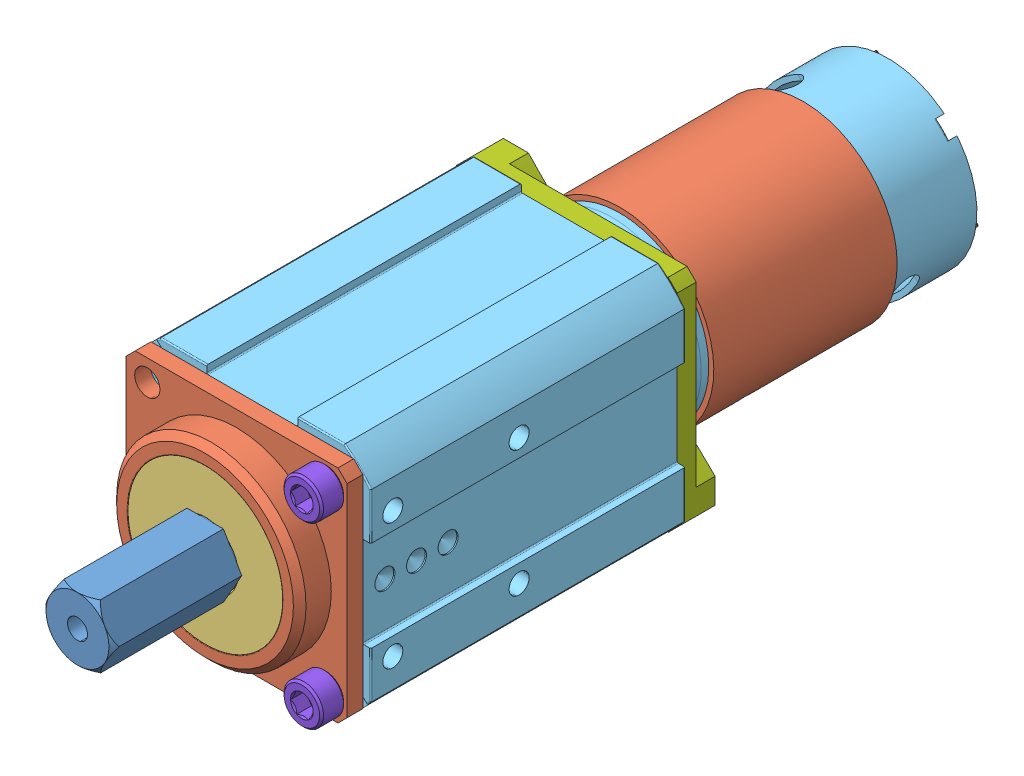
SolidWorks assembly 2018-321-A, configuration Default. Lengths in mm.
Overall size (53.25 53.25 170.06).
44 component instances, 23 part files, 4 mates.
Components (placement in the parent):
- am-3758+-+100_1+-+57+Sport Banebots-1: am-3758+-+100_1+-+57+Sport Banebots [Default] at origin size (48.57 48.57 106.05)
  - am-XXXX - 57 Sport 500 Hex Output Plug-1: am-XXXX - 57 Sport 500 Hex Output Plug [Default] at (24.8149 30.9071 37.1991) size (44.45 44.45 56.9)
    - am-XXXX - 57 Sport 500 Hex Shaft-1: am-XXXX - 57 Sport 500 Hex Shaft [Default] at (0 0 6.2738) x (0.999982 0.006056 0) z (0 0 1) size (16.1 12.67 56.9)
    - Output Block-1: Output Block [Default] at origin size (44.45 44.45 20.32)
    - FR8ZZ Bearing-1: FR8ZZ Bearing [Default] at (8.9053 -5.9773 -13.8938) x (0.999973 0.007281 0) z (0 0 1) size (31.75 31.75 7.95)
    - FR8ZZ Bearing-2: FR8ZZ Bearing [Default] at (5.8713 8.9755 6.2738) x (0.923728 0.383049 0) z (0 0 -1) size (31.75 31.75 7.95)
    - retaining Ring 0500 - Mcm 98410A122_98410A122-1: retaining Ring 0500 - Mcm 98410A122_98410A122 [Default] at (0 0 -14.3891) x (0 0 1) z (-0.999848 0.017452 0) size (0.89 16.1 14.34)
  - am-XXXX - 57 Sport 3 Stage Ring Gear Housing-1: am-XXXX - 57 Sport 3 Stage Ring Gear Housing [Default] at (24.8149 30.9071 2.4011) size (47.68 47.68 63.27)
  - Thrust washer - 775 Sport-1: Thrust washer - 775 Sport [Default] at (24.8149 30.9071 -27.7241) x (0.992053 0.125818 0) z (0 0 1) size (31 31 1.52)
  - am-3765 - 57 Sport Motor Block-1: am-3765 - 57 Sport Motor Block [Default] at (24.8149 30.9071 -33.0319) x (0 1 0) z (0 0 1) size (45.76 47.07 8.89)
  - 10-32 X 375 SHCS_90128A940-1: 10-32 X 375 SHCS_90128A940 [Default] at (42.7754 48.8676 27.6741) x (-0.100111 -0.994976 0) z (0 0 -1) size (7.92 7.92 14.58)
  - 10-32 X 375 SHCS_90128A940-2: 10-32 X 375 SHCS_90128A940 [Default] at (6.8543 12.9466 27.6741) x (0.058911 -0.998263 0) z (0 0 -1) size (7.92 7.92 14.58)
  - 5_1 HD Output Stage-1: 5_1 HD Output Stage [Default] at (-68.9808 196.0711 114.0764) x (-0.524 0.851718 0) z (0 0 -1) size (39.35 39.35 20.95)
    - 5_1 HD Output Stage Carrier Plate-1: 5_1 HD Output Stage Carrier Plate [Default] at (-189.8221 -6.6586 94.2255) size (30.99 30.99 20.93)
    - 18T Long Planet Gear-1: 18T Long Planet Gear [Default] at (-200.8282 -6.6808 106.2401) x (0 0 1) z (0.923728 0.383049 0) size (13.43 13.84 14)
    - 18T Long Planet Gear-2: 18T Long Planet Gear [Default] at (-189.8444 4.3475 106.2401) x (0 0 1) z (0.383049 -0.923728 0) size (13.43 13.84 14)
    - 18T Long Planet Gear-3: 18T Long Planet Gear [Default] at (-178.816 -6.6363 106.2401) x (0 0 1) z (-0.923728 -0.383049 0) size (13.43 13.84 14)
    - 18T Long Planet Gear-4: 18T Long Planet Gear [Default] at (-189.7998 -17.6647 106.2401) x (0 0 1) z (-0.383049 0.923728 0) size (13.43 13.84 14)
  - am-XXXX - 5_1 Sun Gear 4_1 Carrier Plate-1: am-XXXX - 5_1 Sun Gear 4_1 Carrier Plate [Default] at (24.8149 30.9071 -13.6055) x (-0.898594 -0.43878 0) z (0 0 -1) size (40.05 39.58 20.09)
    - 5_1 Sun Gear 57 Sport Stage Carrier Plate-1: 5_1 Sun Gear 57 Sport Stage Carrier Plate [Default] at origin size (31.12 31.12 12.6)
    - 12T Sun Gear-1: 12T Sun Gear [Default] at (3.5865 0.6306 4.6787) x (0 0 1) z (-0.923728 -0.383049 0) size (12.75 9.53 9.53)
    - 16T Planet Gear-1: 16T Planet Gear [Default] at (0.9198 10.3381 9.8136) x (0 0 -1) z (-0.923728 -0.383049 0) size (7.09 12.42 12.42)
    - 16T Planet Gear-2: 16T Planet Gear [Default] at (12.4377 -0.8696 9.8136) x (0 0 -1) z (-0.85131 -0.524663 0) size (7.09 12.42 12.42)
    - 16T Planet Gear-3: 16T Planet Gear [Default] at (1.1732 -12.0926 9.8136) x (0 0 -1) z (-0.777574 -0.628792 0) size (7.09 12.42 12.42)
    - 16T Planet Gear-4: 16T Planet Gear [Default] at (-10.1307 -0.6136 9.8136) x (0 0 -1) z (-0.715577 -0.698533 0) size (7.09 12.42 12.42)
  - am-XXXX - 5_1 Stage-1: am-XXXX - 5_1 Stage [Default] at (24.8149 30.9071 -1.0975) x (-0.884358 0.46681 0) z (0 0 -1) size (37.89 36.82 20.09)
    - 5_1 Stage Carrier Plate-1: 5_1 Stage Carrier Plate [Default] at origin size (31.12 31.12 12.6)
    - 18T Short Planet Gear-1: 18T Short Planet Gear [Default] at (-0.9034 11.1608 11.3032) x (0 0 -1) z (0.019286 0.999814 0) size (7 13.84 14)
    - 18T Short Planet Gear-2: 18T Short Planet Gear [Default] at (9.5654 0.4561 11.3032) x (0 0 -1) z (-0.139481 0.990225 0) size (7 13.84 14)
    - 18T Short Planet Gear-3: 18T Short Planet Gear [Default] at (-1.0383 -10.2271 11.3032) x (0 0 -1) z (-0.264433 0.964404 0) size (7 13.84 14)
    - 18T Short Planet Gear-4: 18T Short Planet Gear [Default] at (-11.6179 0.2284 11.3032) x (0 0 -1) z (-0.353176 0.935557 0) size (7 13.84 14)
    - 12T Sun Gear-1: 12T Sun Gear [Default] at (-3.5865 -0.6306 4.6787) x (0 0 1) z (0.923728 0.383049 0) size (12.75 9.53 9.53)
  - 10-32 X 375 SHCS_90128A940-3: 10-32 X 375 SHCS_90128A940 [Default] at (42.7754 12.9466 27.6741) x (0.058911 -0.998263 0) z (0 0 -1) size (7.92 7.92 14.58)
- CCL-9015-am-0912-1: CCL-9015-am-0912 [Default] at (22.8966 30.5762 -61.5239) x (0 0 -1) z (-0.707107 -0.707107 0) size (82.02 37.83 37.47)
  - AM-0912 terminal-1: AM-0912 terminal [Default] at (29.27 -13.055 -1.5854) size (10.06 0.6 3.8)
  - AM-0912 output bushing-1: AM-0912 output bushing [Default] at (-28.166 1.123 -1.5904) size (4.5 10.97 10.97)
  - AM-0912 end cap-1: AM-0912 end cap [Default] at (24.952 1.123 -1.5904) size (6.48 34.65 34.46)
  - AM-0912 cap bushing-1: AM-0912 cap bushing [Default] at (31.302 1.123 -1.5904) size (3.04 8.08 8.08)
  - AM-0912 shield-1: AM-0912 shield [Default] at (-21.634 1.123 -1.5904) x (1 0 0) z (0 -1 0) size (36.88 37.47 37.83)
  - AM-0912 shaft-1: AM-0912 shaft [Default] at (-32.682 1.123 -1.5904) x (1 0 0) z (0 0.970706 0.240271) size (80.92 3.29 3.26)
  - AM-0912 terminal housing-1: AM-0912 terminal housing [Default] at (30.286 -13.101 -1.5904) x (-1 0 0) z (0 0 1) size (4.06 4.83 19.05)
  - AM-0912 terminal housing-2: AM-0912 terminal housing [Default] at (30.286 15.347 -1.5904) x (-1 0 0) z (0 0 -1) size (4.06 4.83 19.05)
  - AM-0912 terminal-2: AM-0912 terminal [Default] at (29.27 15.301 -1.5954) size (10.06 0.6 3.8)
  - AM-0912 housing-1: AM-0912 housing [Default] at (32.318 1.123 -1.5904) size (61.5 35.8 35.8)
Mates (geometry in assembly coordinates):
- Coincident1: coordinate: point of am-3758+-+100_1+-+57+Sport Banebots-1; point of assembly
- Concentric1: concentric aligned: cylinder of am-3758+-+100_1+-+57+Sport Banebots-1/am-3765 - 57 Sport Motor Block-1 through (24.8149 30.9071 -36.8419) axis (0 0 -1) radius 8.7757; cylinder of CCL-9015-am-0912-1/AM-0912 housing-1 through (24.8153 30.9066 -32.3419) axis (0 0 -1) radius 6.5
- Coincident2: coincident anti-aligned: plane of am-3758+-+100_1+-+57+Sport Banebots-1/am-3765 - 57 Sport Motor Block-1 through (24.8149 30.9071 -36.8419) normal (0 0 -1); plane of CCL-9015-am-0912-1/AM-0912 housing-1 through (24.8153 30.9066 -36.8419) normal (0 0 1)
- Concentric2: concentric aligned: cylinder of am-3758+-+100_1+-+57+Sport Banebots-1/am-3765 - 57 Sport Motor Block-1 through (15.9765 39.7455 -27.9519) axis (0 0 1) radius 1.6; cylinder of CCL-9015-am-0912-1/AM-0912 housing-1 through (15.9765 39.7455 -36.8419) axis (0 0 1) radius 1.25
